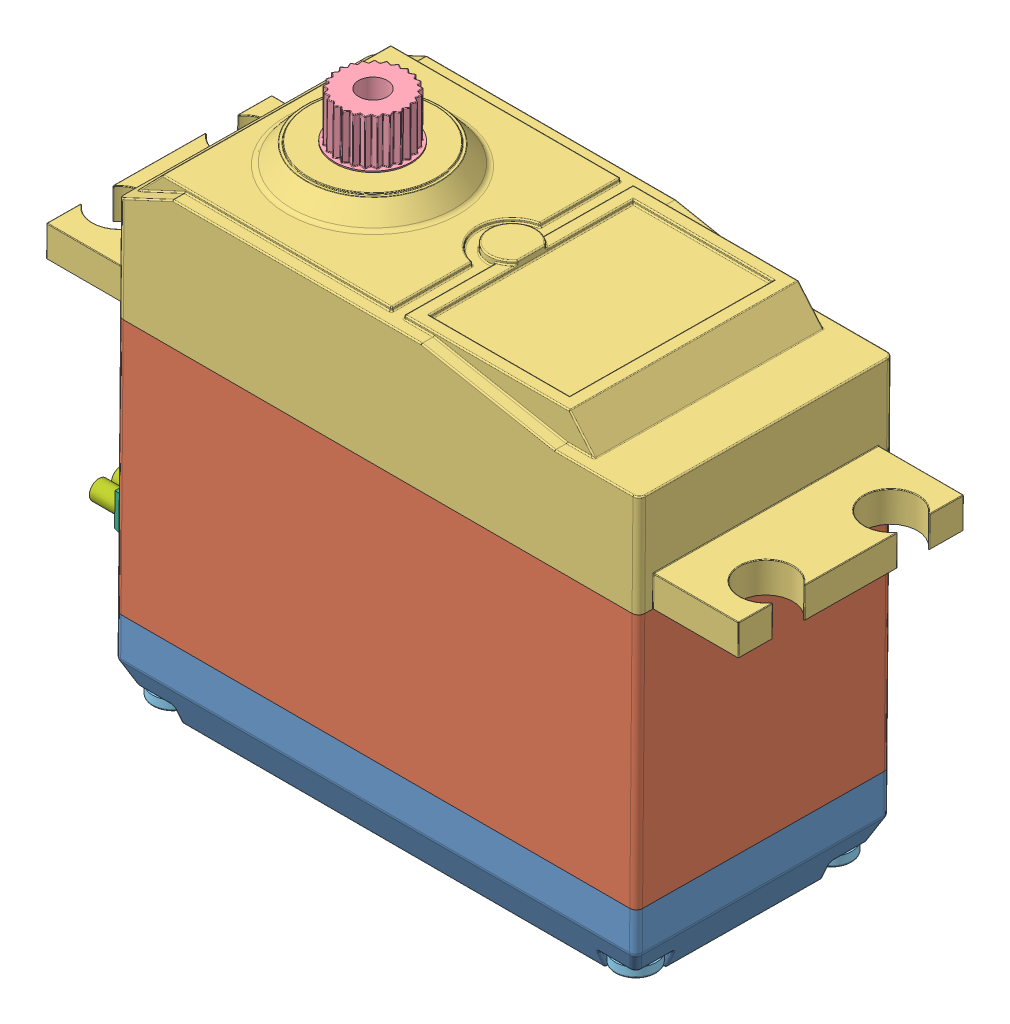
SolidWorks assembly Servomotor SG 5010, configuration Default. Lengths in mm.
Overall size (57.2 42.11 20.33).
10 component instances, 7 part files, 24 mates.
Components (placement in the parent):
- Tap 01-1: Tap 01 [Default] at (2.6095 0.3364 39.8745) x (1 0 0) z (0 -0.008727 -0.999962) size (41 6.5 20)
- Tap 02-1: Tap 02 [Default] at (2.6095 20.3356 39.6999) x (1 0 0) z (0 -0.008727 -0.999962) size (41 20 20)
- Tap 03-1: Tap 03 [Default] at (2.6095 20.3356 39.6999) x (-1 0 0) z (0 -0.008727 -0.999962) size (54.4 11.9 20)
- Eje-1: Eje [Default] at (-7.8905 29.3353 39.6214) x (1 0 0) z (0 0.008727 0.999962) size (6 6.5 6)
- pan head cross recess screw_iso-1: pan head cross recess screw_iso [ISO 7045 - M1.6 x 16 - Z - 16C] at (-15.5814 -5.9305 32.238) x (0 0.999962 -0.008727) z (0.720061 0.006055 0.693884) size (17.27 3.2 3.2)
- pan head cross recess screw_iso-2: pan head cross recess screw_iso [ISO 7045 - M1.6 x 16 - Z - 16C] at (-15.5814 -5.7963 47.6192) x (0 0.999962 -0.008727) z (0.008727 0.008726 0.999924) size (17.27 3.2 3.2)
- pan head cross recess screw_iso-3: pan head cross recess screw_iso [ISO 7045 - M1.6 x 16 - Z - 16C] at (20.8004 -5.7963 47.6192) x (0 0.999962 -0.008727) z (0.008727 0.008726 0.999924) size (17.27 3.2 3.2)
- pan head cross recess screw_iso-4: pan head cross recess screw_iso [ISO 7045 - M1.6 x 16 - Z - 16C] at (20.8004 -5.9305 32.238) x (0 0.999962 -0.008727) z (0.008727 0.008726 0.999924) size (17.27 3.2 3.2)
- Peça1^Servomotor SG 5010-1: Peça1^Servomotor SG 5010 [Valor predeterminado] at (-17.8905 20.3356 39.6999) x (0 -0.008727 -0.999962) z (-1 0 0) size (7.46 5 7.5) (virtual)
- Peça2^Servomotor SG 5010-1: Peça2^Servomotor SG 5010 [Valor predeterminado] at (-25.3905 20.3356 39.6999) x (0 -0.008727 -0.999962) z (-1 0 0) size (4.98 1.5 2) (virtual)
Mates (geometry in assembly coordinates):
- Coincident1: coincident anti-aligned: plane of Tap 01-1 through (2.6095 0.3364 39.8745) normal (0 0.999962 -0.008727); plane of Tap 02-1 through (2.6095 0.3364 39.8745) normal (0 -0.999962 0.008727)
- Coincident2: coincident aligned: plane of Tap 01-1 through (23.1095 -6.1506 29.9307) normal (0 -0.008727 -0.999962); plane of Tap 02-1 through (-17.8905 0.2491 29.8749) normal (0 -0.008727 -0.999962)
- Coincident3: coincident aligned: plane of Tap 01-1 through (-17.8905 -6.1506 29.9307) normal (-1 0 0); plane of Tap 02-1 through (-17.8905 0.2491 29.8749) normal (-1 0 0)
- Coincident4: coincident anti-aligned: plane of Tap 02-1 through (2.6095 20.3356 39.6999) normal (0 0.999962 -0.008727); plane of Tap 03-1 through (2.6095 20.3356 39.6999) normal (0 -0.999962 0.008727)
- Coincident5: coincident aligned: plane of Tap 02-1 through (-17.8905 0.4236 49.8741) normal (0 0.008727 0.999962); plane of Tap 03-1 through (-17.8905 30.4225 49.6123) normal (0 0.008727 0.999962)
- Coincident6: coincident aligned: plane of Tap 02-1 through (-17.8905 0.2491 29.8749) normal (-1 0 0); plane of Tap 03-1 through (-17.8905 30.248 29.6131) normal (-1 0 0)
- Concentric1: concentric anti-aligned: cylinder of Tap 03-1 through (-7.8905 26.1354 39.6493) axis (0 0.999962 -0.008727) radius 3; cylinder of Eje-1 through (-7.8905 32.3352 39.5952) axis (0 -0.999962 0.008727) radius 3
- Distance1: distance = 0.1 mm aligned: plane of Eje-1 through (-7.8905 32.3352 39.5952) normal (0 0.999962 -0.008727); plane of Tap 03-1 through (-7.8905 32.2352 39.5961) normal (0 0.999962 -0.008727)
- Concentric2: concentric aligned: cylinder of Tap 01-1 through (-15.5814 -4.6306 32.2266) axis (0 -0.999962 0.008727) radius 0.875; cylinder of pan head cross recess screw_iso-1 through (-15.5814 -31.3295 32.4596) axis (0 -0.999962 0.008727) radius 1.6
- Coincident7: coincident anti-aligned: plane of Tap 01-1 through (-15.0905 -4.6263 32.7175) normal (0 -0.999962 0.008727); plane of pan head cross recess screw_iso-1 through (-16.1366 -4.6255 32.8026) normal (0 0.999962 -0.008727)
- Concentric3: concentric aligned: cylinder of Tap 01-1 through (-15.5814 -4.4963 47.6079) axis (0 -0.999962 0.008727) radius 0.875; cylinder of pan head cross recess screw_iso-2 through (-15.5814 -31.1953 47.8409) axis (0 -0.999962 0.008727) radius 1.6
- Coincident8: coincident anti-aligned: plane of Tap 01-1 through (-15.0905 -4.5006 47.117) normal (0 -0.999962 0.008727); plane of pan head cross recess screw_iso-2 through (-16.3814 -4.4963 47.6148) normal (0 0.999962 -0.008727)
- Concentric4: concentric aligned: cylinder of Tap 01-1 through (20.8004 -4.4963 47.6079) axis (0 -0.999962 0.008727) radius 0.875; cylinder of pan head cross recess screw_iso-3 through (20.8004 -31.1953 47.8409) axis (0 -0.999962 0.008727) radius 1.6
- Coincident9: coincident anti-aligned: plane of Tap 01-1 through (20.3095 -4.5006 47.117) normal (0 -0.999962 0.008727); plane of pan head cross recess screw_iso-3 through (20.0004 -4.4963 47.6148) normal (0 0.999962 -0.008727)
- Concentric5: concentric aligned: cylinder of Tap 01-1 through (20.8004 -4.6306 32.2266) axis (0 -0.999962 0.008727) radius 0.875; cylinder of pan head cross recess screw_iso-4 through (20.8004 -31.3295 32.4596) axis (0 -0.999962 0.008727) radius 1.6
- Coincident10: coincident anti-aligned: plane of Tap 01-1 through (20.3095 -4.6263 32.7175) normal (0 -0.999962 0.008727); plane of pan head cross recess screw_iso-4 through (20.0004 -4.6305 32.2336) normal (0 0.999962 -0.008727)
- No local1: in place: plane of Tap 02-1 through (-17.8905 0.2491 29.8749) normal (-1 0 0); plane of ? through (-17.8905 0 0) normal (-1 0 0); moOrthogonalPlaneRef_w of Tap 02-1 through (-17.8905 0.2491 29.8749) normal (-1 0 0); plane of ? through (-17.8905 0 0) normal (0 1 0); plane of Tap 02-1 through (-17.8905 0.2491 29.8749) normal (-1 0 0); plane of ? through (-17.8905 0 0) normal (0 0 1); plane of Tap 02-1 through (-17.8905 0.2491 29.8749) normal (-1 0 0); unknown of Peça1^Servomotor SG 5010-1
- Coincidente1: coincident aligned: plane of Tap 02-1; plane of Peça1^Servomotor SG 5010-1
- Coincidente2: coincident aligned: moOrthogonalPlaneRef_w of Tap 02-1 through (-17.8905 20.3356 39.6999) normal (0 -0.999962 0.008727); plane of Peça1^Servomotor SG 5010-1 through (-17.8905 20.3356 39.6999) normal (0 -0.999962 0.008727)
- Coincidente3: coincident anti-aligned: moOrthogonalPlaneRef_w of Tap 02-1 through (-17.8905 20.3356 39.6999) normal (0 0.008727 0.999962); plane of Peça1^Servomotor SG 5010-1 through (-17.8905 20.3356 39.6999) normal (0 -0.008727 -0.999962)
- No local2: in place: plane of Peça1^Servomotor SG 5010-1 through (-25.3905 20.3356 39.6999) normal (-1 0 0); plane of ? through (-25.3905 0 0) normal (-1 0 0); plane of Peça1^Servomotor SG 5010-1 through (-25.3905 20.3356 39.6999) normal (-1 0 0); plane of ? through (-25.3905 0 0) normal (0 1 0); plane of Peça1^Servomotor SG 5010-1 through (-25.3905 20.3356 39.6999) normal (-1 0 0); plane of ? through (-25.3905 0 0) normal (0 0 1); plane of Peça1^Servomotor SG 5010-1 through (-25.3905 20.3356 39.6999) normal (-1 0 0); unknown of Peça2^Servomotor SG 5010-1
- Coincidente4: coincident aligned: plane of Peça1^Servomotor SG 5010-1; plane of Peça2^Servomotor SG 5010-1
- Coincidente5: coincident aligned: moOrthogonalPlaneRef_w of Peça1^Servomotor SG 5010-1 through (-25.3905 20.3356 39.6999) normal (0 -0.999962 0.008727); plane of Peça2^Servomotor SG 5010-1 through (-25.3905 20.3356 39.6999) normal (0 -0.999962 0.008727)
- Coincidente6: coincident anti-aligned: moOrthogonalPlaneRef_w of Peça1^Servomotor SG 5010-1 through (-25.3905 20.3356 39.6999) normal (0 0.008727 0.999962); plane of Peça2^Servomotor SG 5010-1 through (-25.3905 20.3356 39.6999) normal (0 -0.008727 -0.999962)
